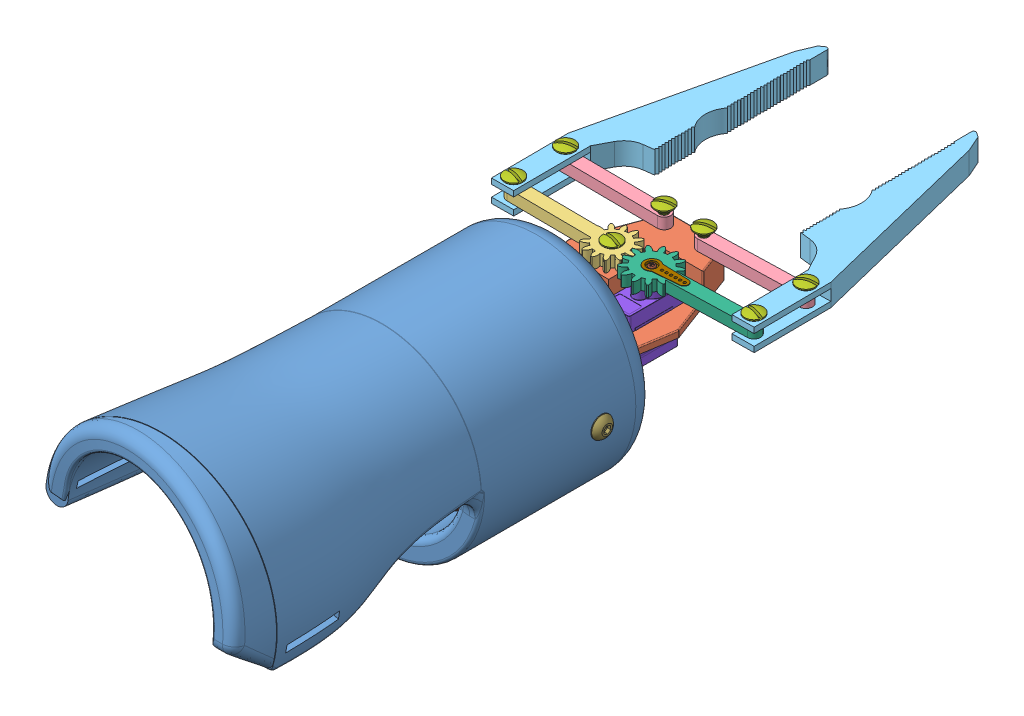
SolidWorks assembly FinalAssembly, configuration Default. Lengths in mm.
Overall size (236.56 116.77 396.65).
23 component instances, 12 part files, 6 mates.
Components (placement in the parent):
- Armconnecter2-1: Armconnecter2 [Default] at (87.7991 170.1543 116.8278) size (115.45 116.77 211.32)
- ClawMK2-1: ClawMK2 [Default] at (92.5151 92.9699 83.5121) x (-0.353674 0 -0.935369) z (0.935369 0 -0.353674) size (237.13 69 164.08)
  - Base-1: Base [Default] at (-1.2919 74.4344 -5.5304) x (-0.353674 0 0.935369) z (-0.935369 0 -0.353674) size (69 69 125)
  - Gear2_nocutout-1: Gear2_nocutout [Default] at (70.4031 95.9472 -61.1761) x (0 1 0) z (-0.488869 0 0.872357) size (5 20.52 57.89)
  - Connector-1: Connector [Default] at (34.9527 88.2344 -25.5015) x (0.361605 0 -0.932332) z (0.932332 0 0.361605) size (51 5 6)
  - Claw-3: Claw [Default] at (32.5803 85.7344 -50.3822) x (0.937424 0 0.348189) z (-0.348189 0 0.937424) size (127.16 10 26.59)
  - Gear1-2: Gear1 [Default] at (-12.105 95.9472 85.1522) x (0 1 0) z (-0.295007 0 -0.955495) size (5 40.44 50.3)
  - Claw-4: Claw [Default] at (-4.8116 95.7344 50.9526) x (0.938317 0 0.345776) z (0.345776 0 -0.938317) size (127.16 10 26.59)
  - Connector-3: Connector [Default] at (13.0787 88.2344 33.5706) x (-0.327636 0 0.944804) z (-0.944804 0 -0.327636) size (51 5 6)
  - countersunk slotted raised head screw_iso-1: countersunk slotted raised head screw_iso [ISO 2010 - M4 x 12 - 12N] at (20.8625 97.6344 -54.7346) x (0 -1 0) z (-0.546944 0 0.837169) size (12.98 8.4 8.31)
  - countersunk slotted raised head screw_iso-3: countersunk slotted raised head screw_iso [ISO 2010 - M4 x 12 - 12N] at (43.0888 97.6344 -46.479) x (0 -1 0) z (0 0 1) size (12.98 8.4 8.31)
  - countersunk slotted raised head screw_iso-4: countersunk slotted raised head screw_iso [ISO 2010 - M4 x 12 - 12N] at (26.8166 97.4344 -4.5241) x (0 -1 0) z (0 0 1) size (12.98 8.4 8.31)
  - countersunk slotted raised head screw_iso-5: countersunk slotted raised head screw_iso [ISO 2010 - M4 x 12 - 12N] at (20.4505 97.4344 12.3126) x (0 -1 0) z (0 0 1) size (12.98 8.4 8.31)
  - countersunk slotted raised head screw_iso-6: countersunk slotted raised head screw_iso [ISO 2010 - M4 x 12 - 12N] at (-16.5406 97.6344 46.6304) x (0 -1 0) z (-0.546944 0 0.837169) size (12.98 8.4 8.31)
  - countersunk slotted raised head screw_iso-7: countersunk slotted raised head screw_iso [ISO 2010 - M4 x 12 - 12N] at (5.7069 97.6344 54.8287) x (0 -1 0) z (0 0 1) size (12.98 8.4 8.31)
  - countersunk slotted raised head screw_iso-8: countersunk slotted raised head screw_iso [ISO 2010 - M4 x 12 - 12N] at (4.5903 95.1344 -12.7796) x (0 -1 0) z (-0.546944 0 0.837169) size (12.98 8.4 8.31)
  - SG90 - Micro Servo 9g - Tower Pro.1-1: SG90 - Micro Servo 9g - Tower Pro.1 [Peça] at (-6.618 72.2844 2.2915) x (-0.935369 0 -0.353674) z (0.353674 0 -0.935369) size (32.1 29.95 12.4)
  - SG90 - Micro Servo 9g - Tower Pro.2-3: SG90 - Micro Servo 9g - Tower Pro.2 [Peça] at (-1.8008 93.3844 4.1129) x (0.326685 0 -0.945133) z (0.945133 0 0.326685) size (19.5 3.8 6.9)
  - SG90 - Micro Servo 9g - Tower Pro.5-1: SG90 - Micro Servo 9g - Tower Pro.5 [BS EN ISO 7045 - M2 x 8 - Z - 8S] at (-19.6196 81.5344 -2.6246) x (0 -1 0) z (0 0 1) size (9.57 4.8 4.8)
  - SG90 - Micro Servo 9g - Tower Pro.5-2: SG90 - Micro Servo 9g - Tower Pro.5 [BS EN ISO 7045 - M2 x 8 - Z - 8S] at (6.3836 81.5344 7.2075) x (0 -1 0) z (0 0 1) size (9.57 4.8 4.8)
  - SG90 - Micro Servo 9g - Tower Pro.6-5: SG90 - Micro Servo 9g - Tower Pro.6 [BS EN ISO 7045 - M2 x 4 - Z - 4S] at (-1.8008 93.6844 4.1129) x (0 -1 0) z (0 0 1) size (5.28 3.1 3.1)
- socket button head screw_iso-2: socket button head screw_iso [ISO 7380 - M5 x 20 - 20N] at (135.5491 170.1543 142.4725) x (-1 0 0) z (0 0.125791 -0.992057) size (22.75 9.5 9.5)
- socket button head screw_iso-4: socket button head screw_iso [ISO 7380 - M5 x 20 - 20N] at (40.0491 170.1543 142.4725) size (22.75 9.5 9.5)
Mates (geometry in assembly coordinates):
- Concentric2: concentric aligned: cylinder of Armconnecter2-1 through (87.7991 170.1543 196.8278) axis (0 0 -1) radius 35; cylinder of ClawMK2-1/Base-1 through (87.7991 170.1543 179.1764) axis (0 0 -1) radius 34.5
- Parallel1: parallel aligned: cylinder of Armconnecter2-1 through (33.8198 170.1543 142.4725) axis (1 0 0) radius 2.5; cylinder of ClawMK2-1/Base-1 through (53.2991 169.4043 140.7111) axis (1 0 0) radius 2.5
- Concentric3: concentric aligned: cylinder of Armconnecter2-1 through (33.8198 170.1543 142.4725) axis (1 0 0) radius 2.5; cylinder of socket button head screw_iso-2 through (135.5491 170.1543 142.4725) axis (1 0 0) radius 2.5
- Tangent7: tangent anti-aligned: cylinder of Armconnecter2-1 through (87.7991 170.1543 196.8278) axis (0 0 -1) radius 45; plane of socket button head screw_iso-2 through (132.7991 172.6344 142.7869) normal (-1 0 0)
- Concentric4: concentric anti-aligned: cylinder of Armconnecter2-1 through (33.8198 170.1543 142.4725) axis (1 0 0) radius 2.5; cylinder of socket button head screw_iso-4 through (40.0491 170.1543 142.4725) axis (-1 0 0) radius 2.5
- Tangent8: tangent anti-aligned: cylinder of Armconnecter2-1 through (87.7991 170.1543 196.8278) axis (0 0 -1) radius 45; plane of socket button head screw_iso-4 through (42.7991 172.6543 142.4725) normal (1 0 0)
